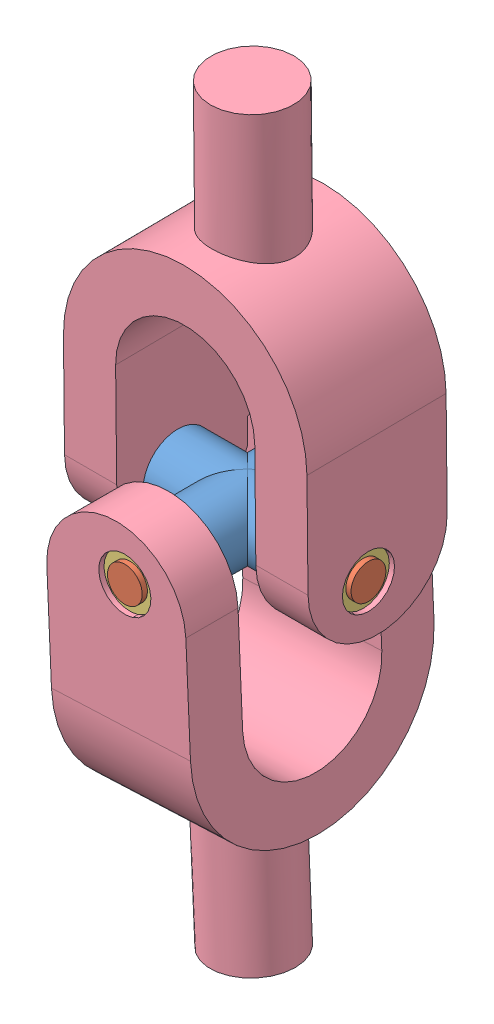
SolidWorks assembly Assem2, configuration Default. Lengths in mm.
Overall size (88.9 272.91 88.9).
11 component instances, 4 part files, 17 mates.
Components (placement in the parent):
- swivel-1: swivel [Default] at (39.7243 27.6085 41.0632) size (54.61 25.4 54.61)
- Pin-1: Pin [Default] at (84.1743 27.164 41.3277) x (0 -0.074147 0.997247) z (-1 0 0) size (12.7 12.7 34.29)
- Pin-2: Pin [Default] at (39.4164 25.9774 51.2232) x (0.925661 -0.378355 0) z (0 0 1) size (12.7 12.7 34.29)
- Pin-3: Pin [Default] at (39.5395 26.0449 -3.3868) size (12.7 12.7 34.29)
- Pin-4: Pin [Default] at (29.5643 27.4076 41.3719) x (0 -0.324855 0.945764) z (-1 0 0) size (12.7 12.7 34.29)
- Bushing-1: Bushing [Default] at (39.4164 25.9774 68.3682) size (19.05 19.05 15.24)
- Bushing-8: Bushing [Default] at (39.5395 26.0449 -1.4818) x (0.999701 -0.024438 0) z (0 0 1) size (19.05 19.05 15.24)
- Bushing-9: Bushing [Default] at (-2.8207 27.4076 41.3719) x (0 0 -1) z (1 0 0) size (19.05 19.05 15.24)
- Bushing-10: Bushing [Default] at (67.0293 27.164 41.3277) x (0 0 -1) z (1 0 0) size (19.05 19.05 15.24)
- Part3ASS2-3: Part3ASS2 [Default] at (39.7243 72.4294 12.9823) x (1 0 0) z (0 -0.010231 0.999948) size (88.9 153.67 50.8)
- Part3ASS2-4: Part3ASS2 [Default] at (12.6361 -20.2312 41.0632) x (0 0 1) z (0.999012 0.044432 0) size (88.9 153.67 50.8)
Mates (geometry in assembly coordinates):
- Coincident22: coincident anti-aligned: plane of swivel-1 through (39.7243 27.6085 68.3682) normal (0 0 1); plane of Bushing-1 through (39.4164 25.9774 68.3682) normal (0 0 -1)
- Coincident23: coincident anti-aligned: plane of swivel-1 through (39.7243 27.6085 13.7582) normal (0 0 -1); circle of Bushing-8
- Coincident24: coincident anti-aligned: plane of swivel-1 through (12.4193 27.6085 41.0632) normal (-1 0 0); plane of Bushing-9 through (12.4193 27.4076 41.3719) normal (1 0 0)
- Coincident29: coincident anti-aligned: plane of swivel-1 through (67.0293 27.6085 41.0632) normal (1 0 0); plane of Bushing-10 through (67.0293 27.164 41.3277) normal (-1 0 0)
- Concentric9: concentric anti-aligned: cylinder of Pin-1 through (49.8843 27.164 41.3277) axis (1 0 0) radius 6.35; cylinder of Bushing-10 through (82.2693 27.164 41.3277) axis (-1 0 0) radius 6.35
- Concentric10: concentric aligned: cylinder of Pin-3 through (39.5395 26.0449 30.9032) axis (0 0 -1) radius 6.35; cylinder of Bushing-8 through (39.5395 26.0449 13.7582) axis (0 0 -1) radius 6.35
- Concentric11: concentric aligned: cylinder of Pin-2 through (39.4164 25.9774 85.5132) axis (0 0 -1) radius 6.35; cylinder of Bushing-1 through (39.4164 25.9774 83.6082) axis (0 0 -1) radius 6.35
- Concentric16: concentric anti-aligned: cylinder of Pin-4 through (-4.7257 27.4076 41.3719) axis (1 0 0) radius 6.35; cylinder of Bushing-9 through (12.4193 27.4076 41.3719) axis (-1 0 0) radius 6.35
- Concentric21: concentric aligned: cylinder of Pin-1 through (49.8843 27.164 41.3277) axis (1 0 0) radius 6.35; cylinder of Part3ASS2-3 through (84.1743 27.164 41.3277) axis (1 0 0) radius 9.525
- Concentric24: concentric anti-aligned: cylinder of Pin-2 through (39.4164 25.9774 85.5132) axis (0 0 -1) radius 6.35; cylinder of Part3ASS2-4 through (39.4164 25.9774 85.5132) axis (0 0 1) radius 9.525
- Width2: width aligned: plane of Part3ASS2-3 through (84.1743 71.9097 63.7796) normal (1 0 0); plane of Bushing-10 through (-4.7257 71.9097 63.7796) normal (-1 0 0); plane of Part3ASS2-3 through (82.2693 27.164 41.3277) normal (1 0 0); plane of Bushing-9 through (-2.8207 27.4076 41.3719) normal (-1 0 0)
- Width3: width aligned: plane of Part3ASS2-4 through (63.3859 -17.974 -3.3868) normal (0 0 -1); plane of Bushing-8 through (63.3859 -17.974 85.5132) normal (0 0 1); plane of Part3ASS2-4 through (39.5395 26.0449 -1.4818) normal (0 0 -1); plane of Bushing-1 through (39.4164 25.9774 83.6082) normal (0 0 1)
- Coincident31: coincident aligned: plane of Pin-4 through (-4.7257 27.4076 41.3719) normal (-1 0 0); plane of Part3ASS2-3 through (-4.7257 71.9097 63.7796) normal (-1 0 0)
- Coincident32: coincident anti-aligned: circle of Pin-1; plane of Part3ASS2-3 through (84.1743 71.9097 63.7796) normal (1 0 0)
- Coincident33: coincident aligned: plane of Pin-2 through (39.4164 25.9774 85.5132) normal (0 0 1); plane of Part3ASS2-4 through (63.3859 -17.974 85.5132) normal (0 0 1)
- Parallel6: parallel aligned: plane of Pin-3 through (39.5395 26.0449 -3.3868) normal (0 0 -1); plane of Part3ASS2-4 through (63.3859 -17.974 -3.3868) normal (0 0 -1)
- Coincident40: coincident aligned: plane of Pin-3 through (39.5395 26.0449 -3.3868) normal (0 0 -1); plane of Part3ASS2-4 through (63.3859 -17.974 -3.3868) normal (0 0 -1)
